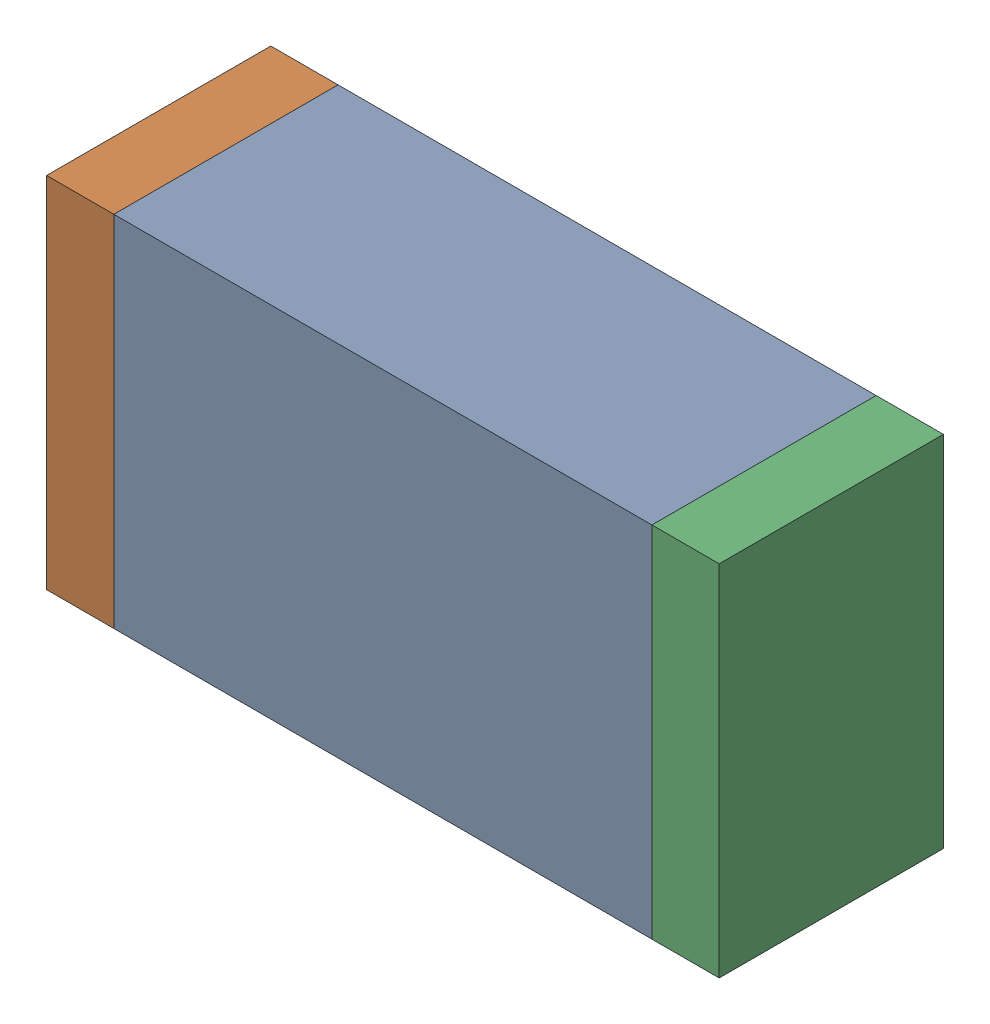
SolidWorks assembly D12, configuration Default. Lengths in mm.
Overall size (1.5 0.8 0.5).
6 component instances, 2 part files, 0 mates.
Components (placement in the parent):
- 836752368-1: 836752368 [Default] at (111.2 27.75 0) size (1.2 0.8 0.5)
  - Extruded-1: Extruded [Default] at origin size (1.2 0.8 0.5)
- 836752496-1: 836752496 [Default] at (110.525 27.75 0) size (0.15 0.8 0.5)
  - Extruded_2-1: Extruded_2 [Default] at origin size (0.15 0.8 0.5)
- 836752496-2: 836752496 [Default] at (111.875 27.75 0) size (0.15 0.8 0.5)
  - Extruded_2-1: Extruded_2 [Default] at origin size (0.15 0.8 0.5)
